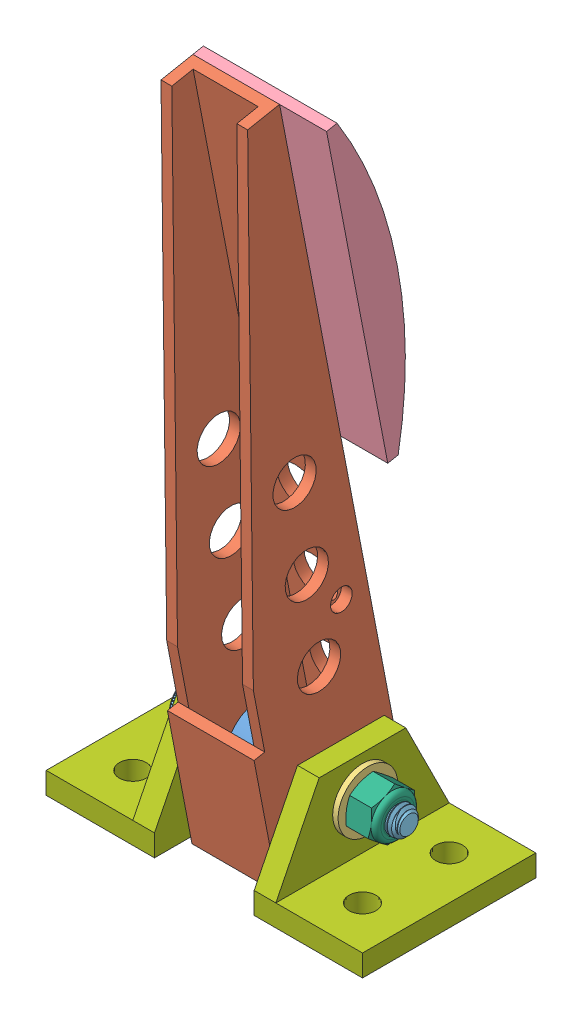
SolidWorks assembly Accelerator Pedal, configuration Default. Lengths in mm.
Overall size (92.71 202.5 78.86).
11 component instances, 8 part files, 22 mates.
Components (placement in the parent):
- Pedal Shaft Housing-1: Pedal Shaft Housing [Default] at (32.4162 -0.0905 155.2954) x (1 0 0) z (0 0.947536 0.319648) size (25.4 19.05 19.05)
- Pedal-1: Pedal [Default] at (32.4162 179.8255 171.3419) x (1 0 0) z (0 -0.981992 -0.188924) size (25.4 38.1 196.57)
- Flanged Sleeve-1: Flanged Sleeve [2938T36] at (67.6587 -0.0905 155.2954) x (0 0.840414 -0.541945) z (0 0.541945 0.840414) size (17.46 6.35 17.46)
- Flanged Sleeve-2: Flanged Sleeve [2938T36] at (22.5737 -0.0905 155.2954) x (0 0.416306 -0.909225) z (0 -0.909225 -0.416306) size (17.46 6.35 17.46)
- Narrow Pedal Pad-1: Narrow Pedal Pad [Default] at (32.4162 86.6649 153.4189) x (1 0 0) z (0 -0.188924 0.981992) size (39.18 94.87 11.96)
- Steel Socket Shoulder 5_16in-18 1and3_4in-1: Steel Socket Shoulder 5_16in-18 1and3_4in [91259A630] at (22.5737 -0.0905 155.2954) x (0 0.94719 -0.320672) z (0 0.320672 0.94719) size (14.29 64 14.29)
- Steel Nyloc 5_16-24 Grade 5-1: Steel Nyloc 5_16-24 Grade 5 [95615A170] at (67.6587 -0.0905 155.2954) x (0 0.139525 0.990219) z (0 0.990219 -0.139525) size (12.7 8.97 14.66)
- Accelerator Mount-1: Accelerator Mount [Default] at (-7.5888 -20.4105 129.8954) x (0 0 1) z (-1 0 0) size (50.8 31.75 31.75)
- Accelerator Mount-2: Accelerator Mount [Default] at (97.8212 -20.4105 180.6954) x (0 0 -1) z (1 0 0) size (50.8 31.75 31.75)
- PTFE 3_8in ID 5_8in OD Washer-3: PTFE 3_8in ID 5_8in OD Washer [92150A163] at (57.8162 -0.0905 155.2954) x (0 -1 0) z (0 0 1) size (15.88 1.91 15.88)
- PTFE 3_8in ID 5_8in OD Washer-4: PTFE 3_8in ID 5_8in OD Washer [92150A163] at (32.4162 -0.0905 155.2954) x (0 1 0) z (0 0 1) size (15.88 1.91 15.88)
Mates (geometry in assembly coordinates):
- Concentric1: concentric anti-aligned: cylinder of Pedal Shaft Housing-1 through (57.8162 -0.0905 155.2954) axis (-1 0 0) radius 9.525; cylinder of Pedal-1 through (32.4162 -0.0905 155.2954) axis (1 0 0) radius 9.5123
- Coincident2: coincident aligned: plane of Pedal Shaft Housing-1 through (32.4162 -0.0905 155.2954) normal (-1 0 0); plane of Pedal-1 through (32.4162 -13.2052 134.205) normal (-1 0 0)
- Coincident5: coincident anti-aligned: plane of Pedal-1 through (32.4162 -13.2052 134.205) normal (0 0.188924 -0.981992); plane of Narrow Pedal Pad-1 through (71.5957 86.6649 153.4189) normal (0 -0.188924 0.981992)
- Coincident6: coincident aligned: plane of Pedal-1 through (32.4162 -13.2052 134.205) normal (-1 0 0); plane of Narrow Pedal Pad-1 through (32.4162 110.6444 279.8548) normal (-1 0 0)
- Coincident7: coincident aligned: plane of Pedal-1 through (32.4162 179.8255 171.3419) normal (0 0.981992 0.188924); plane of Narrow Pedal Pad-1 through (71.5957 179.8255 171.3419) normal (0 0.981992 0.188924)
- Concentric8: concentric aligned: cylinder of Steel Socket Shoulder 5_16in-18 1and3_4in-1 through (22.5737 -0.0905 155.2954) axis (1 0 0) radius 4.7625; cylinder of Accelerator Mount-2 through (59.7202 -0.0905 155.2954) axis (1 0 0) radius 6.3627
- Concentric9: concentric aligned: cylinder of Steel Socket Shoulder 5_16in-18 1and3_4in-1 through (22.5737 -0.0905 155.2954) axis (-1 0 0) radius 2.993; cylinder of Steel Nyloc 5_16-24 Grade 5-1 through (77.66 -0.0905 155.2954) axis (-1 0 0) radius 4.1753
- Coincident15: coincident aligned: plane of Accelerator Mount-1 through (-7.5888 -20.4105 180.6954) normal (0 -1 0); plane of Accelerator Mount-2 through (97.8212 -20.4105 129.8954) normal (0 -1 0)
- Coincident20: coincident anti-aligned: plane of Flanged Sleeve-1 through (66.0712 -0.0905 155.2954) normal (-1 0 0); plane of Accelerator Mount-2 through (66.0712 -20.4105 129.8954) normal (1 0 0)
- Concentric11: concentric aligned: circle of Flanged Sleeve-1; circle of Accelerator Mount-2
- Coincident21: coincident anti-aligned: plane of Flanged Sleeve-2 through (24.1612 -0.0905 155.2954) normal (1 0 0); plane of Accelerator Mount-1 through (24.1612 -20.4105 180.6954) normal (-1 0 0)
- Concentric12: concentric aligned: cylinder of Flanged Sleeve-2 through (28.9237 -0.0905 155.2954) axis (-1 0 0) radius 4.7879; cylinder of Accelerator Mount-1 through (30.5122 -0.0905 155.2954) axis (-1 0 0) radius 6.3627
- Concentric13: concentric anti-aligned: circle of Accelerator Mount-2; circle of PTFE 3_8in ID 5_8in OD Washer-3
- Coincident22: coincident anti-aligned: plane of Accelerator Mount-2 through (59.7212 -20.4105 129.8954) normal (-1 0 0); plane of PTFE 3_8in ID 5_8in OD Washer-3 through (59.7212 -0.0905 155.2954) normal (1 0 0)
- Concentric14: concentric anti-aligned: circle of Accelerator Mount-1; circle of PTFE 3_8in ID 5_8in OD Washer-4
- Coincident23: coincident anti-aligned: plane of Accelerator Mount-1 through (30.5112 -20.4105 180.6954) normal (1 0 0); plane of PTFE 3_8in ID 5_8in OD Washer-4 through (30.5112 -0.0905 155.2954) normal (-1 0 0)
- Coincident24: coincident anti-aligned: plane of Flanged Sleeve-2 through (22.5737 -0.0905 155.2954) normal (-1 0 0); plane of Steel Socket Shoulder 5_16in-18 1and3_4in-1 through (22.5737 -0.0905 155.2954) normal (1 0 0)
- Concentric15: concentric anti-aligned: cylinder of Flanged Sleeve-2 through (28.9237 -0.0905 155.2954) axis (-1 0 0) radius 4.7879; cylinder of Steel Socket Shoulder 5_16in-18 1and3_4in-1 through (22.5737 -0.0905 155.2954) axis (1 0 0) radius 4.7625
- Coincident25: coincident anti-aligned: plane of Flanged Sleeve-1 through (67.6587 -0.0905 155.2954) normal (1 0 0); plane of Steel Nyloc 5_16-24 Grade 5-1 through (67.6587 -7.3511 156.3184) normal (-1 0 0)
- Concentric16: concentric anti-aligned: cylinder of Pedal Shaft Housing-1 through (57.8162 -0.0905 155.2954) axis (-1 0 0) radius 4.7879; cylinder of Steel Socket Shoulder 5_16in-18 1and3_4in-1 through (22.5737 -0.0905 155.2954) axis (1 0 0) radius 4.7625
- Coincident26: coincident anti-aligned: plane of Pedal Shaft Housing-1 through (57.8162 -0.0905 155.2954) normal (1 0 0); plane of PTFE 3_8in ID 5_8in OD Washer-3 through (57.8162 -0.0905 155.2954) normal (-1 0 0)
- Coincident27: coincident anti-aligned: plane of Pedal Shaft Housing-1 through (32.4162 -0.0905 155.2954) normal (-1 0 0); plane of PTFE 3_8in ID 5_8in OD Washer-4 through (32.4162 -0.0905 155.2954) normal (1 0 0)
